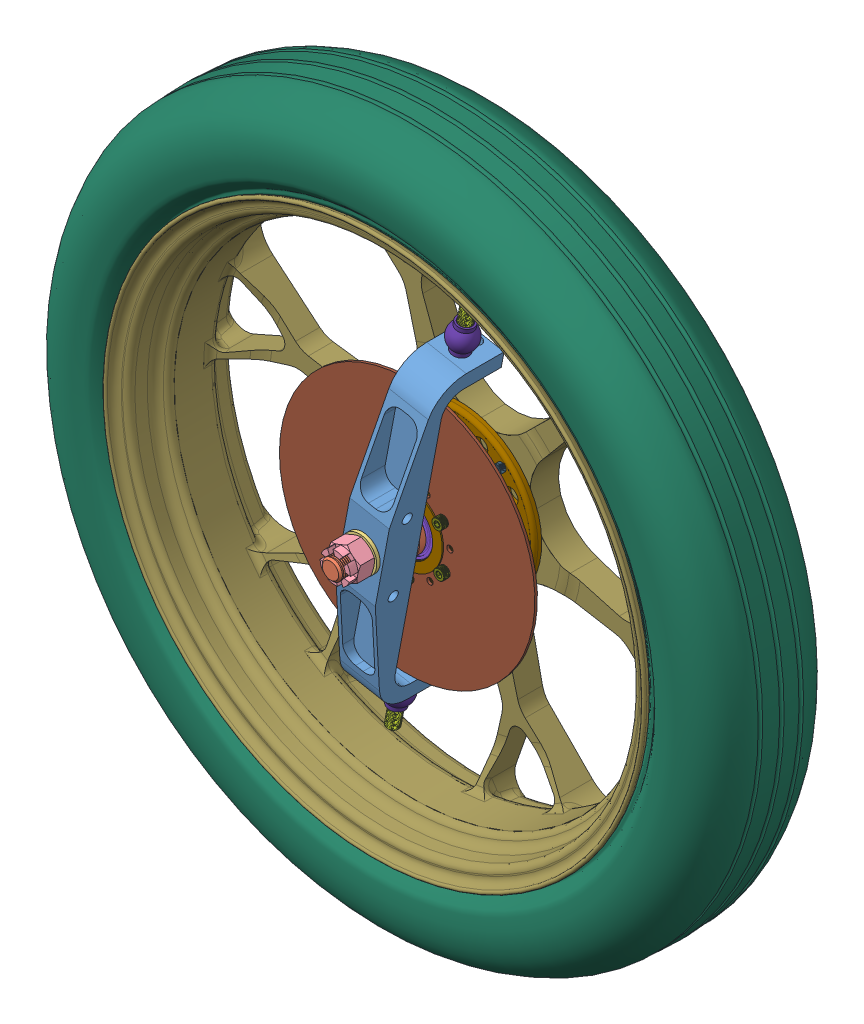
SolidWorks assembly SpindleAssy, configuration Default. Lengths in mm.
Overall size (616.2 616.2 20000).
35 component instances, 18 part files, 67 mates.
Components (placement in the parent):
- Knuckle-1: Knuckle [Default] at (82.0121 130.0239 204.0915) size (78.12 253.33 73.5)
- Spindle_Light-1: Spindle_Light [Default] at (82.0121 130.0239 204.0915) x (0 0 -1) z (0.185408 0.982662 0) size (50000 34 30)
- M16 98688A121_General Purpose Zinc-Plated Steel Washer-1: M16 98688A121_General Purpose Zinc-Plated Steel Washer [98688A121] at (82.0121 130.0239 232.5915) x (0.99983 -0.018445 0) z (0 0 1) size (28 28 2.7)
- M16x1-5 93760A128_Steel Locknut for Use with Cotter Pins-1: M16x1-5 93760A128_Steel Locknut for Use with Cotter Pins [93760A128] at (82.0121 130.0239 254.2915) x (0.982886 -0.184217 0) z (0 0 1) size (24 27.71 19.76)
- M14 98689A119_General Purpose 18-8 Stainless Steel Washer-1: M14 98689A119_General Purpose 18-8 Stainless Steel Washer [98689A119] at (82.0121 130.0239 138.2415) size (24 24 2.7)
- M14x1-5 93760A127_Steel Locknut for Use with Cotter Pins-1: M14x1-5 93760A127_Steel Locknut for Use with Cotter Pins [93760A127] at (82.0121 130.0239 120.8915) x (-0.661913 -0.74958 0) z (0 0 -1) size (22 25.4 16.76)
- 91257A659_Zinc Yellow-Chromate Plated Hex Head Screw-2: 91257A659_Zinc Yellow-Chromate Plated Hex Head Screw [91257A659] at (107.2476 263.7718 178.2059) x (0.185408 0.982662 0) z (0.110595 -0.020867 0.993646) size (57.6 16.5 14.29)
- 91257A659_Zinc Yellow-Chromate Plated Hex Head Screw-3: 91257A659_Zinc Yellow-Chromate Plated Hex Head Screw [91257A659] at (56.7767 -3.724 178.2059) x (-0.185408 -0.982662 0) z (-0.565974 0.106788 0.817478) size (57.6 16.5 14.29)
- SteerArm-1: SteerArm [Default] at (97.7347 127.0573 218.3415) x (0 0 -1) z (0.982662 -0.185408 0) (suppressed, hidden)
- SKF_6004-2Z.stp-1: SKF_6004-2Z.stp [Default] at (82.0121 130.0239 185.0915) x (0 0 1) z (-0.58163 0.813454 0) size (12 42 42)
- Hub5-16-1: Hub5-16 [Default] at (82.0121 130.0239 173.6746) x (0.677885 0.735168 0) z (0.735168 -0.677885 0) size (130 85 130)
- SKF_6003-2Z.stp-1: SKF_6003-2Z.stp [Default] at (82.0121 130.0239 149.5915) x (0 0 -1) z (0.973183 -0.230032 0) size (10 35 35)
- BasicBrakeDisc-1: BasicBrakeDisc [Default] at (82.0121 130.0239 195.0915) x (0.885567 -0.464511 0) z (0 0 1) size (203.2 203.2 2)
- rimmachined v13.2-1: rimmachined v13.2 [Default] at (82.0121 130.0239 177.3915) x (0 0 -1) z (0.218956 0.975735 0) size (93.59 431.57 431.57)
- 92415A381_Zinc-Plated Steel Unthreaded Spacer-2: 92415A381_Zinc-Plated Steel Unthreaded Spacer [92415A381] at (138.5979 117.294 155.2387) size (7.94 7.94 7.21)
- 92415A381_Zinc-Plated Steel Unthreaded Spacer-3: 92415A381_Zinc-Plated Steel Unthreaded Spacer [92415A381] at (121.3294 172.6636 155.2387) size (7.94 7.94 7.21)
- 92415A381_Zinc-Plated Steel Unthreaded Spacer-4: 92415A381_Zinc-Plated Steel Unthreaded Spacer [92415A381] at (64.7437 185.3935 155.2387) size (7.94 7.94 7.21)
- 92415A381_Zinc-Plated Steel Unthreaded Spacer-5: 92415A381_Zinc-Plated Steel Unthreaded Spacer [92415A381] at (25.4263 142.7538 155.2387) size (7.94 7.94 7.21)
- 92415A381_Zinc-Plated Steel Unthreaded Spacer-6: 92415A381_Zinc-Plated Steel Unthreaded Spacer [92415A381] at (42.6948 87.3841 155.2387) size (7.94 7.94 7.21)
- 92415A381_Zinc-Plated Steel Unthreaded Spacer-7: 92415A381_Zinc-Plated Steel Unthreaded Spacer [92415A381] at (99.2806 74.6542 155.2387) size (7.94 7.94 7.21)
- 8-32x3-8 92196A192_18-8 Stainless Steel Socket Head Screw-1: 8-32x3-8 92196A192_18-8 Stainless Steel Socket Head Screw [92196A192] at (25.4263 142.7538 158.4118) size (6.85 6.85 14.15)
- 8-32x3-8 92196A192_18-8 Stainless Steel Socket Head Screw-2: 8-32x3-8 92196A192_18-8 Stainless Steel Socket Head Screw [92196A192] at (64.7437 185.3935 158.4118) size (6.85 6.85 14.15)
- 8-32x3-8 92196A192_18-8 Stainless Steel Socket Head Screw-3: 8-32x3-8 92196A192_18-8 Stainless Steel Socket Head Screw [92196A192] at (42.6948 87.3841 158.4118) size (6.85 6.85 14.15)
- 8-32x3-8 92196A192_18-8 Stainless Steel Socket Head Screw-4: 8-32x3-8 92196A192_18-8 Stainless Steel Socket Head Screw [92196A192] at (99.2806 74.6542 158.4118) size (6.85 6.85 14.15)
- 8-32x3-8 92196A192_18-8 Stainless Steel Socket Head Screw-5: 8-32x3-8 92196A192_18-8 Stainless Steel Socket Head Screw [92196A192] at (138.5979 117.294 158.4118) size (6.85 6.85 14.15)
- 8-32x3-8 92196A192_18-8 Stainless Steel Socket Head Screw-6: 8-32x3-8 92196A192_18-8 Stainless Steel Socket Head Screw [92196A192] at (121.3294 172.6636 158.4118) size (6.85 6.85 14.15)
- Michelin Tire-1: Michelin Tire [Default] at (82.0121 130.0239 177.3915) x (0 0 1) z (-0.993534 -0.113534 0) size (101.13 556.61 556.61)
- M5x10 91290A224_Alloy Steel Socket Head Screw-1: M5x10 91290A224_Alloy Steel Socket Head Screw [91290A224] at (112.1214 114.2305 194.5915) x (0.901899 0.431946 0) z (0 0 1) size (8.5 8.5 15.31)
- M5x10 91290A224_Alloy Steel Socket Head Screw-2: M5x10 91290A224_Alloy Steel Socket Head Screw [91290A224] at (110.7442 148.2026 194.5915) x (-0.609316 -0.792927 0) z (0 0 1) size (8.5 8.5 15.31)
- M5x10 91290A224_Alloy Steel Socket Head Screw-3: M5x10 91290A224_Alloy Steel Socket Head Screw [91290A224] at (83.3893 96.0518 194.5915) x (0.740699 0.671837 0) z (0 0 1) size (8.5 8.5 15.31)
- M5x10 91290A224_Alloy Steel Socket Head Screw-4: M5x10 91290A224_Alloy Steel Socket Head Screw [91290A224] at (53.28 111.8451 194.5915) x (-0.161403 -0.986889 0) z (0 0 1) size (8.5 8.5 15.31)
- M5x10 91290A224_Alloy Steel Socket Head Screw-5: M5x10 91290A224_Alloy Steel Socket Head Screw [91290A224] at (80.6349 163.996 194.5915) x (0.079005 -0.996874 0) z (0 0 1) size (8.5 8.5 15.31)
- M5x10 91290A224_Alloy Steel Socket Head Screw-6: M5x10 91290A224_Alloy Steel Socket Head Screw [91290A224] at (51.9028 145.8172 194.5915) x (-0.159143 -0.987256 0) z (0 0 1) size (8.5 8.5 15.31)
- BallSuper-Swivel  Joint Rod End6960T231_-1: BallSuper-Swivel  Joint Rod End6960T231_ [6960T231] at (60.3806 -5.3072 159.5459) x (0.962544 -0.181612 0.20131) z (-0.185408 -0.982662 0) size (20.64 20.64 22.23)
- BallSuper-Swivel  Joint Rod End6960T231_-2: BallSuper-Swivel  Joint Rod End6960T231_ [6960T231] at (109.0836 264.3285 197.1798) x (0.978736 -0.184667 -0.089292) z (0.185408 0.982662 0) size (20.64 20.64 22.23)
Mates (geometry in assembly coordinates):
- Coincident1: coincident anti-aligned: circle of Knuckle-1; circle of Spindle_Light-1
- Concentric1: concentric aligned: circle of Knuckle-1; circle of M16 98688A121_General Purpose Zinc-Plated Steel Washer-1
- Concentric2: concentric aligned: circle of M16 98688A121_General Purpose Zinc-Plated Steel Washer-1; circle of M16x1-5 93760A128_Steel Locknut for Use with Cotter Pins-1
- Coincident2: coincident anti-aligned: plane of Knuckle-1 through (82.0121 130.0239 232.5915) normal (0 0 1); plane of M16 98688A121_General Purpose Zinc-Plated Steel Washer-1 through (82.0121 130.0239 232.5915) normal (0 0 -1)
- Coincident3: coincident anti-aligned: plane of M16 98688A121_General Purpose Zinc-Plated Steel Washer-1 through (82.0121 130.0239 235.2915) normal (0 0 1); plane of M16x1-5 93760A128_Steel Locknut for Use with Cotter Pins-1 through (84.5647 143.6431 235.2915) normal (0 0 -1)
- Parallel1: parallel aligned: plane of Spindle_Light-1 through (82.0121 130.0239 258.0915) normal (0 0 1); plane of M16x1-5 93760A128_Steel Locknut for Use with Cotter Pins-1 through (82.0121 130.0239 248.2915) normal (0 0 1)
- Concentric3: concentric anti-aligned: circle of M14 98689A119_General Purpose 18-8 Stainless Steel Washer-1; circle of M14x1-5 93760A127_Steel Locknut for Use with Cotter Pins-1
- Coincident5: coincident anti-aligned: plane of M14 98689A119_General Purpose 18-8 Stainless Steel Washer-1 through (82.0121 130.0239 136.8915) normal (0 0 -1); plane of M14x1-5 93760A127_Steel Locknut for Use with Cotter Pins-1 through (75.0117 150.8804 136.8915) normal (0 0 1)
- Concentric4: concentric anti-aligned: circle of Spindle_Light-1; circle of M14 98689A119_General Purpose 18-8 Stainless Steel Washer-1
- Perpendicular1: perpendicular: line of Knuckle-1 through (84.6232 230.1587 204.0915) axis (-0.185408 -0.982662 0); line of Spindle_Light-1 through (76.9319 146.2471 204.0915) axis (0.982662 -0.185408 0)
- Concentric5: concentric aligned: circle of Knuckle-1; circle of Super-Swivel Ball Joint Ball End2-1
- Coincident7: coincident anti-aligned: plane of Knuckle-1 through (89.6292 256.6906 232.5915) normal (0.185408 0.982662 0); plane of Super-Swivel Ball Joint Ball End2-1 through (107.5018 254.0508 172.0915) normal (-0.20131 -0.979528 0)
- Concentric6: concentric anti-aligned: circle of Knuckle-1; circle of Super-Swivel Ball Joint Ball End2-2
- Coincident8: coincident anti-aligned: plane of Knuckle-1 through (74.395 3.3572 232.5915) normal (-0.185408 -0.982662 0); plane of Super-Swivel Ball Joint Ball End2-2 through (56.5224 5.997 172.0915) normal (0.20131 0.979528 0)
- Coincident9: coincident aligned: circle of Knuckle-1; circle of 91257A659_Zinc Yellow-Chromate Plated Hex Head Screw-2
- Coincident10: coincident anti-aligned: circle of Knuckle-1; circle of 91257A659_Zinc Yellow-Chromate Plated Hex Head Screw-3
- Coincident11: coincident anti-aligned: circle of Knuckle-1; circle of SteerArm-1
- Coincident12: coincident anti-aligned: circle of Knuckle-1; circle of SteerArm-1
- Concentric7: concentric anti-aligned: circle of Spindle_Light-1; circle of SKF_6004-2Z.stp-1
- Coincident13: coincident anti-aligned: plane of Spindle_Light-1 through (70.2202 132.2488 197.0915) normal (0 0 -1); plane of SKF_6004-2Z.stp-1 through (90.6347 136.1891 197.0915) normal (0 0 1)
- Coincident14: coincident anti-aligned: plane of SKF_6004-2Z.stp-1 through (98.6066 141.8891 185.0915) normal (0 0 -1); plane of Hub5-16-1 through (94.8919 143.9921 185.0915) normal (0 0 1)
- Concentric8: concentric aligned: cylinder of SKF_6004-2Z.stp-1 through (82.0121 130.0239 235.0915) axis (0 0 1) radius 21; cylinder of Hub5-16-1 through (82.0121 130.0239 1099.7023) axis (0 0 1) radius 21
- Concentric9: concentric anti-aligned: cylinder of Hub5-16-1 through (82.0121 130.0239 1099.7023) axis (0 0 1) radius 17.5; cylinder of SKF_6003-2Z.stp-1 through (82.0121 130.0239 99.5915) axis (0 0 -1) radius 17.5
- Coincident15: coincident anti-aligned: plane of Hub5-16-1 through (92.5193 141.419 149.5915) normal (0 0 -1); plane of SKF_6003-2Z.stp-1 through (85.9687 146.7626 149.5915) normal (0 0 1)
- Coincident16: coincident anti-aligned: plane of M14 98689A119_General Purpose 18-8 Stainless Steel Washer-1 through (82.0121 130.0239 139.5915) normal (0 0 1); plane of SKF_6003-2Z.stp-1 through (84.0364 138.5879 139.5915) normal (0 0 -1)
- Concentric10: concentric aligned: circle of Hub5-16-1; circle of BasicBrakeDisc-1
- Coincident18: coincident anti-aligned: plane of Hub5-16-1 through (101.6708 151.3437 195.0915) normal (0 0 1); plane of BasicBrakeDisc-1 through (82.0121 130.0239 195.0915) normal (0 0 -1)
- Concentric11: concentric anti-aligned: cylinder of Hub5-16-1 through (82.0121 130.0239 1099.7023) axis (0 0 1) radius 47; cylinder of rimmachined v13.2-1 through (82.0121 130.0239 168.2915) axis (0 0 -1) radius 47.005
- Coincident19: coincident aligned: circle of Hub5-16-1; circle of 92415A381_Zinc-Plated Steel Unthreaded Spacer-5
- Coincident20: coincident aligned: circle of Hub5-16-1; circle of 92415A381_Zinc-Plated Steel Unthreaded Spacer-4
- Coincident21: coincident aligned: circle of Hub5-16-1; circle of 92415A381_Zinc-Plated Steel Unthreaded Spacer-3
- Coincident22: coincident aligned: circle of Hub5-16-1; circle of 92415A381_Zinc-Plated Steel Unthreaded Spacer-2
- Coincident23: coincident aligned: circle of Hub5-16-1; circle of 92415A381_Zinc-Plated Steel Unthreaded Spacer-7
- Coincident24: coincident aligned: circle of Hub5-16-1; circle of 92415A381_Zinc-Plated Steel Unthreaded Spacer-6
- Concentric121: concentric anti-aligned: cylinder of Hub5-16-1 through (25.4263 142.7538 151.0915) axis (0 0 1) radius 2.15; cylinder of 8-32x3-8 92196A192_18-8 Stainless Steel Socket Head Screw-1 through (25.4263 142.7538 151.5665) axis (0 0 -1) radius 2.0828
- Coincident251: coincident anti-aligned: plane of Hub5-16-1 through (124.041 175.6043 161.0915) normal (0 0 1); plane of 8-32x3-8 92196A192_18-8 Stainless Steel Socket Head Screw-1 through (22.1688 142.7538 161.0915) normal (0 0 -1)
- Concentric131: concentric anti-aligned: cylinder of Hub5-16-1 through (64.7437 185.3935 151.0915) axis (0 0 1) radius 2.15; cylinder of 8-32x3-8 92196A192_18-8 Stainless Steel Socket Head Screw-2 through (64.7437 185.3935 151.5665) axis (0 0 -1) radius 2.0828
- Coincident261: coincident anti-aligned: plane of Hub5-16-1 through (124.041 175.6043 161.0915) normal (0 0 1); plane of 8-32x3-8 92196A192_18-8 Stainless Steel Socket Head Screw-2 through (61.4861 185.3935 161.0915) normal (0 0 -1)
- Concentric141: concentric anti-aligned: cylinder of Hub5-16-1 through (42.6948 87.3841 151.0915) axis (0 0 1) radius 2.15; cylinder of 8-32x3-8 92196A192_18-8 Stainless Steel Socket Head Screw-3 through (42.6948 87.3841 151.5665) axis (0 0 -1) radius 2.0828
- Coincident271: coincident anti-aligned: plane of Hub5-16-1 through (124.041 175.6043 161.0915) normal (0 0 1); plane of 8-32x3-8 92196A192_18-8 Stainless Steel Socket Head Screw-3 through (39.4372 87.3841 161.0915) normal (0 0 -1)
- Concentric151: concentric anti-aligned: cylinder of Hub5-16-1 through (99.2806 74.6542 151.0915) axis (0 0 1) radius 2.15; cylinder of 8-32x3-8 92196A192_18-8 Stainless Steel Socket Head Screw-4 through (99.2806 74.6542 151.5665) axis (0 0 -1) radius 2.0828
- Coincident281: coincident anti-aligned: plane of Hub5-16-1 through (124.041 175.6043 161.0915) normal (0 0 1); plane of 8-32x3-8 92196A192_18-8 Stainless Steel Socket Head Screw-4 through (96.023 74.6542 161.0915) normal (0 0 -1)
- Concentric161: concentric anti-aligned: cylinder of Hub5-16-1 through (138.5979 117.294 151.0915) axis (0 0 1) radius 2.15; cylinder of 8-32x3-8 92196A192_18-8 Stainless Steel Socket Head Screw-5 through (138.5979 117.294 151.5665) axis (0 0 -1) radius 2.0828
- Coincident291: coincident anti-aligned: plane of Hub5-16-1 through (124.041 175.6043 161.0915) normal (0 0 1); plane of 8-32x3-8 92196A192_18-8 Stainless Steel Socket Head Screw-5 through (135.3403 117.294 161.0915) normal (0 0 -1)
- Concentric171: concentric anti-aligned: cylinder of Hub5-16-1 through (121.3294 172.6636 151.0915) axis (0 0 1) radius 2.15; cylinder of 8-32x3-8 92196A192_18-8 Stainless Steel Socket Head Screw-6 through (121.3294 172.6636 151.5665) axis (0 0 -1) radius 2.0828
- Coincident301: coincident anti-aligned: plane of Hub5-16-1 through (124.041 175.6043 161.0915) normal (0 0 1); plane of 8-32x3-8 92196A192_18-8 Stainless Steel Socket Head Screw-6 through (118.0719 172.6636 161.0915) normal (0 0 -1)
- Tangent1: tangent anti-aligned: plane of rimmachined v13.2-1 through (28.7347 146.0789 150.7915) normal (-0.218956 -0.975735 0); cylinder of 92415A381_Zinc-Plated Steel Unthreaded Spacer-5 through (25.4263 142.7538 151.6669) axis (0 0 1) radius 3.9688
- Coincident31: coincident anti-aligned: plane of Hub5-16-1 through (113.8727 164.5768 155.0915) normal (0 0 -1); plane of rimmachined v13.2-1 through (42.9827 138.7821 155.0915) normal (0 0 1)
- Concentric18: concentric aligned: cone of rimmachined v13.2-1 through (82.0121 130.0239 200.42) axis (0 0 -1); cylinder of Michelin Tire-1 through (82.0121 130.0239 74.6686) axis (0 0 -1) radius 203
- Coincident32: coincident anti-aligned: plane of rimmachined v13.2-1 through (82.0121 130.0239 177.3915) normal (0 0 -1); plane of Michelin Tire-1 through (82.0121 130.0239 177.3915) normal (0 0 1)
- Concentric19: concentric anti-aligned: cylinder of Hub5-16-1 through (115.9842 131.4011 185.0915) axis (0 0 1) radius 2; cylinder of BasicBrakeDisc-1 through (115.9842 131.4011 197.0915) axis (0 0 -1) radius 2.497
- Concentric20: concentric anti-aligned: circle of BasicBrakeDisc-1; circle of M5x10 91290A224_Alloy Steel Socket Head Screw-2
- Coincident33: coincident anti-aligned: plane of BasicBrakeDisc-1 through (82.0121 130.0239 197.0915) normal (0 0 1); plane of M5x10 91290A224_Alloy Steel Socket Head Screw-2 through (113.1815 151.3743 197.0915) normal (0 0 -1)
- Concentric21: concentric anti-aligned: circle of BasicBrakeDisc-1; circle of M5x10 91290A224_Alloy Steel Socket Head Screw-1
- Concentric22: concentric anti-aligned: circle of BasicBrakeDisc-1; circle of M5x10 91290A224_Alloy Steel Socket Head Screw-3
- Concentric23: concentric anti-aligned: circle of BasicBrakeDisc-1; circle of M5x10 91290A224_Alloy Steel Socket Head Screw-4
- Concentric24: concentric anti-aligned: circle of BasicBrakeDisc-1; circle of M5x10 91290A224_Alloy Steel Socket Head Screw-6
- Concentric25: concentric anti-aligned: circle of BasicBrakeDisc-1; circle of M5x10 91290A224_Alloy Steel Socket Head Screw-5
- Coincident34: coincident anti-aligned: plane of BasicBrakeDisc-1 through (82.0121 130.0239 197.0915) normal (0 0 1); plane of M5x10 91290A224_Alloy Steel Socket Head Screw-1 through (108.5138 112.5027 197.0915) normal (0 0 -1)
- Coincident36: coincident anti-aligned: plane of BasicBrakeDisc-1 through (82.0121 130.0239 197.0915) normal (0 0 1); plane of M5x10 91290A224_Alloy Steel Socket Head Screw-3 through (80.4265 93.3644 197.0915) normal (0 0 -1)
- Coincident37: coincident anti-aligned: plane of BasicBrakeDisc-1 through (82.0121 130.0239 197.0915) normal (0 0 1); plane of M5x10 91290A224_Alloy Steel Socket Head Screw-5 through (80.3189 167.9835 197.0915) normal (0 0 -1)
- Coincident38: coincident anti-aligned: plane of BasicBrakeDisc-1 through (82.0121 130.0239 197.0915) normal (0 0 1); plane of M5x10 91290A224_Alloy Steel Socket Head Screw-6 through (52.5394 149.7663 197.0915) normal (0 0 -1)
- Coincident39: coincident anti-aligned: plane of BasicBrakeDisc-1 through (82.0121 130.0239 197.0915) normal (0 0 1); plane of M5x10 91290A224_Alloy Steel Socket Head Screw-4 through (53.9256 115.7927 197.0915) normal (0 0 -1)
- Concentric172: concentric aligned: cylinder of 91257A659_Zinc Yellow-Chromate Plated Hex Head Screw-2 through (103.1269 241.9321 178.2059) axis (0.185408 0.982662 0) radius 4.7625; cone of BallSuper-Swivel  Joint Rod End6960T231_-2 through (105.3518 253.724 178.2059) axis (0.185408 0.982662 0)
- Coincident302: coincident anti-aligned: plane of Knuckle-1 through (89.6292 256.6906 232.5915) normal (0.185408 0.982662 0); plane of BallSuper-Swivel  Joint Rod End6960T231_-2 through (105.3518 253.724 178.2059) normal (-0.185408 -0.982662 0)
- Concentric173: concentric aligned: cylinder of 91257A659_Zinc Yellow-Chromate Plated Hex Head Screw-3 through (60.8973 18.1156 178.2059) axis (-0.185408 -0.982662 0) radius 4.7625; cone of BallSuper-Swivel  Joint Rod End6960T231_-1 through (58.6725 6.3237 178.2059) axis (-0.185408 -0.982662 0)
- Coincident303: coincident anti-aligned: plane of Knuckle-1 through (74.395 3.3572 232.5915) normal (-0.185408 -0.982662 0); plane of BallSuper-Swivel  Joint Rod End6960T231_-1 through (58.6725 6.3237 178.2059) normal (0.185408 0.982662 0)
